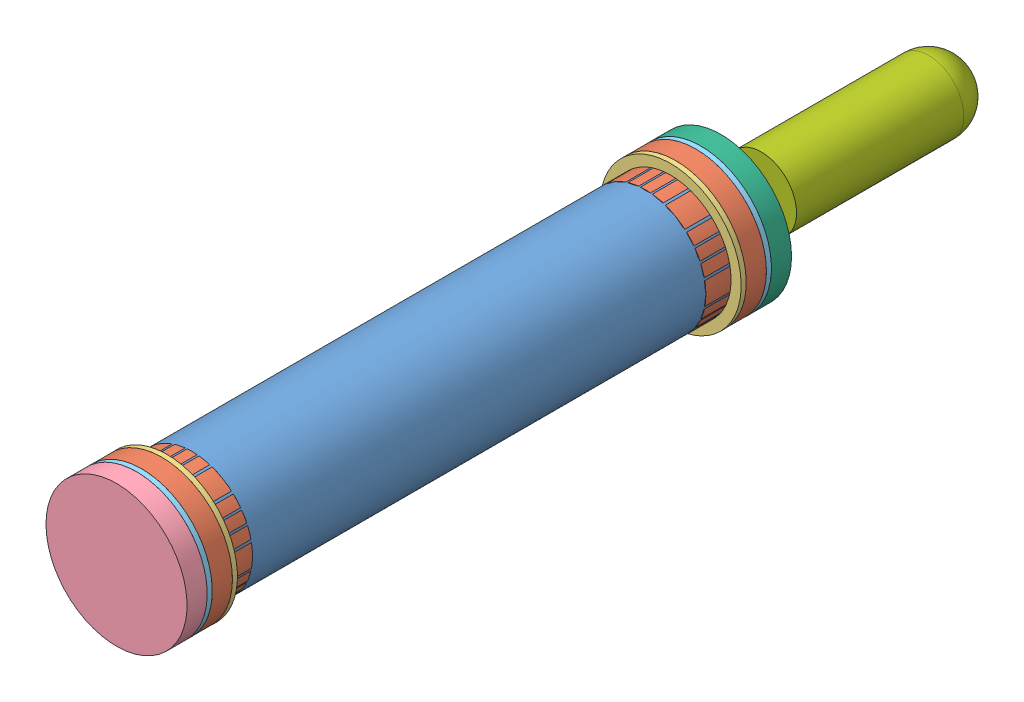
SolidWorks assembly Assemblage2, configuration Défaut. Lengths in mm.
Overall size (70 70 420).
10 component instances, 7 part files, 18 mates.
Components (placement in the parent):
- PVC de 60mm-1: PVC de 60mm [Défaut] at (-1.2188 -3.5722 250) size (60 60 250)
- support-2: support [Défaut] at (-1.2188 -3.5722 247.5) size (70 70 30)
- joint toride-1: joint toride [Défaut] at (-1.1188 -3.9721 247.5) size (70 70 2.5)
- support-3: support [Défaut] at (-1.2188 -3.5722 502.5) x (-1 0 0) z (0 0 -1) size (70 70 30)
- joint toride-2: joint toride [Défaut] at (-1.1188 -3.9721 500) size (70 70 2.5)
- bouchon bas-2: bouchon bas [Défaut] at (-1.2188 -3.5722 515) x (-1 0 0) z (0 0 -1) size (70 70 40)
- joint toride 2-1: joint toride 2 [Défaut] at (-0.3669 -3.5722 512.5) size (70 70 2.5)
- bouchon HAUT -1: bouchon HAUT  [Défaut] at (-1.2188 -3.5722 235) size (70 70 50)
- joint toride 2-2: joint toride 2 [Défaut] at (-0.3669 -3.5722 235) size (70 70 2.5)
- micro-1: micro [Défaut] at (-1.2188 -3.5722 105) size (35 35 125)
Mates (geometry in assembly coordinates):
- Coaxiale2: concentric aligned: cylinder of support-2 through (-1.2188 -3.5722 267.5) axis (0 0 -1) radius 30; cylinder of joint toride-1 through (-1.2188 -3.5722 250) axis (0 0 -1) radius 30
- Coïncidente2: coincident anti-aligned: plane of support-2 through (-1.2188 -3.5722 247.5) normal (0 0 1); plane of joint toride-1 through (-1.2188 -3.5722 247.5) normal (0 0 -1)
- Coïncidente3: coincident anti-aligned: plane of PVC de 60mm-1 through (-1.2188 -3.5722 250) normal (0 0 -1); plane of joint toride-1 through (-1.2188 -3.5722 250) normal (0 0 1)
- Coaxiale4: concentric aligned: cylinder of PVC de 60mm-1 through (-1.2188 -3.5722 500) axis (0 0 -1) radius 29; cylinder of support-2 through (-1.2188 -3.5722 267.5) axis (0 0 -1) radius 30
- Coaxiale5: concentric anti-aligned: cylinder of support-3 through (-1.2188 -3.5722 482.5) axis (0 0 1) radius 30; cylinder of joint toride-2 through (-1.2188 -3.5722 502.5) axis (0 0 -1) radius 30
- Coïncidente4: coincident anti-aligned: plane of support-3 through (-1.2188 -3.5722 502.5) normal (0 0 -1); plane of joint toride-2 through (-1.2188 -3.5722 502.5) normal (0 0 1)
- Coïncidente5: coincident anti-aligned: plane of PVC de 60mm-1 through (-1.2188 -3.5722 500) normal (0 0 1); plane of joint toride-2 through (-1.2188 -3.5722 500) normal (0 0 -1)
- Coaxiale6: concentric anti-aligned: cylinder of PVC de 60mm-1 through (-1.2188 -3.5722 500) axis (0 0 -1) radius 29; cylinder of support-3 through (-1.2188 -3.5722 482.5) axis (0 0 1) radius 30
- Coaxiale8: concentric anti-aligned: cylinder of bouchon bas-2 through (-1.2188 -3.5722 495) axis (0 0 1) radius 24; cylinder of joint toride 2-1 through (-1.2188 -3.5722 515) axis (0 0 -1) radius 24
- Coïncidente7: coincident anti-aligned: plane of bouchon bas-2 through (-1.2188 -3.5722 515) normal (0 0 -1); plane of joint toride 2-1 through (-1.2188 -3.5722 515) normal (0 0 1)
- Coaxiale9: concentric aligned: cylinder of support-3 through (-1.2188 -3.5722 482.5) axis (0 0 1) radius 25; cylinder of bouchon bas-2 through (-1.2188 -3.5722 495) axis (0 0 1) radius 24
- Coïncidente8: coincident anti-aligned: plane of support-3 through (-1.2188 -3.5722 512.5) normal (0 0 1); plane of joint toride 2-1 through (-1.2188 -3.5722 512.5) normal (0 0 -1)
- Coaxiale10: concentric aligned: cylinder of bouchon HAUT -1 through (-1.2188 -3.5722 265) axis (0 0 -1) radius 24; cylinder of joint toride 2-2 through (-1.2188 -3.5722 237.5) axis (0 0 -1) radius 24
- Coïncidente9: coincident anti-aligned: plane of bouchon HAUT -1 through (-1.2188 -3.5722 235) normal (0 0 1); plane of joint toride 2-2 through (-1.2188 -3.5722 235) normal (0 0 -1)
- Coaxiale11: concentric aligned: cylinder of support-2 through (-1.2188 -3.5722 267.5) axis (0 0 -1) radius 25; cylinder of bouchon HAUT -1 through (-1.2188 -3.5722 265) axis (0 0 -1) radius 24
- Coïncidente10: coincident anti-aligned: plane of support-2 through (-1.2188 -3.5722 237.5) normal (0 0 -1); plane of joint toride 2-2 through (-1.2188 -3.5722 237.5) normal (0 0 1)
- Coaxiale12: concentric aligned: circle of bouchon HAUT -1; cylinder of micro-1 through (-1.2188 -3.5722 230) axis (0 0 -1) radius 2
- Distance1: distance = 20 mm anti-aligned: plane of bouchon HAUT -1 through (-1.2188 -3.5722 225) normal (0 0 -1); plane of micro-1 through (-1.2188 -3.5722 205) normal (0 0 1)
